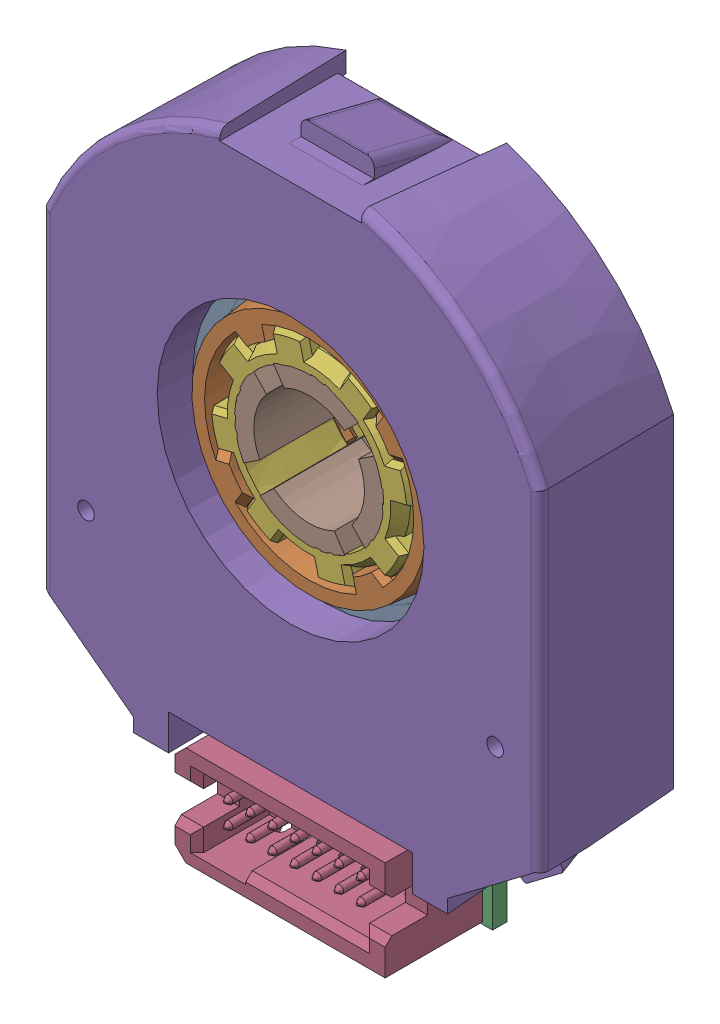
SolidWorks assembly CUI_DEVICES_CUI_DEVICES_AMT203-0096-6350-W, configuration Default. Lengths in mm.
Overall size (28.58 37.22 9.46).
10 component instances, 8 part files, 0 mates.
Components (placement in the parent):
- CUI_DEVICES_Overmold_Rev_A-1: CUI_DEVICES_Overmold_Rev_A [Default] at (2.4928 -19.3128 13.7932) x (0.994004 -0.10934 0) z (0 0 1) size (25.6 25.6 6.65)
  - CUI_DEVICES_Rotor_16f_5c_Rev_D-1: CUI_DEVICES_Rotor_16f_5c_Rev_D [Default] at (-4.5895 18.9245 -10.5857) size (25.6 25.6 0.31)
  - CUI_DEVICES_AMT-Overmold_Hub-REV_A-1: CUI_DEVICES_AMT-Overmold_Hub-REV_A [Default] at (-4.5895 18.9245 -10.5807) x (-0.941518 -0.336962 0) z (0 0 1) size (14.07 14.07 6.65)
- CUI_DEVICES_Transmitter-board with connector(standard connector)-1: CUI_DEVICES_Transmitter-board with connector(standard connector) [Default] at (19.1596 -17.1102 1.69) x (-1 0 0) z (0 0 -1) size (26.63 35.37 7.65)
  - CUI_DEVICES_Transmitter-board(AMT203-303)-1: CUI_DEVICES_Transmitter-board(AMT203-303) [Default] at origin size (26.63 35.37 1.96)
  - CUI_DEVICES_TFM-107-01-X-D-A-1: CUI_DEVICES_TFM-107-01-X-D-A [Default] at (25.2099 -1.9489 -0.84) x (1 0 0) z (0 1 0) size (12.06 7.65 5.72)
- CUI_DEVICES_AMT-203_303-Top-Cover_Rev_H-1: CUI_DEVICES_AMT-203_303-Top-Cover_Rev_H [Default] at (0 0 6.23) x (-1 0 0) z (0 0 -1) size (28.58 32.71 7.83)
- CUI_DEVICES_AMT-Shaft-Adaptor-REVD_Fixed-1: CUI_DEVICES_AMT-Shaft-Adaptor-REVD_Fixed [Default] at (0 0 1.2125) x (0.970396 0.24152 0) z (0 0 1) size (11.8 11.8 7.8)
- CUI_DEVICES_Receiver-board-1: CUI_DEVICES_Receiver-board [Default] at (72.2834 -20.351 4.19) x (-1 0 0) z (0 0 -1) size (26.5 26.62 0.41)
- CUI_DEVICES_AMT-Sleeve-REV-D(D)-1: CUI_DEVICES_AMT-Sleeve-REV-D(D) [Default] at (0 0 -1.3375) x (0.994004 -0.10934 0) z (0 0 1) size (10.79 10.79 7.8)
